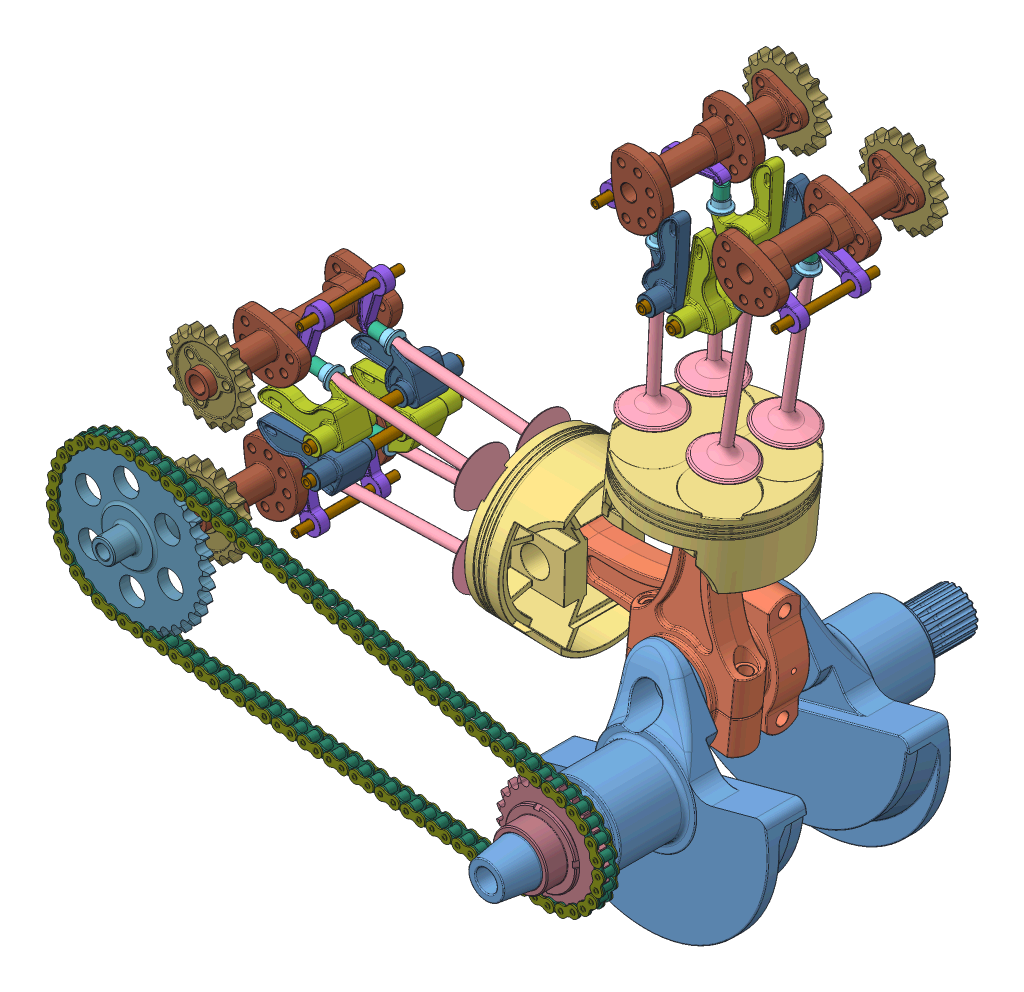
SolidWorks assembly Top Level Assembly, configuration Default. Lengths in mm.
Overall size (642.54 685.71 462).
171 component instances, 16 part files, 41 mates.
Components (placement in the parent):
- Flywheel Final-1: Flywheel Final [Taper Shaft] x (0.965926 0.258819 0) z (0 0 1) size (239.43 220 247)
- Conrod Final-1: Conrod Final [ConRod Cup] at (-15.5291 57.9555 -64) x (0.994894 -0.100925 0) z (0 0 1) size (117 45 42.18)
- Conrod Final-2: Conrod Final [ConRod] at (-15.5291 57.9555 -64) x (0.994894 -0.100925 0) z (0 0 1) size (117.32 192.67 42.18)
- Flywheel Final-2: Flywheel Final [Spline Shaft] at (0 0 -180) x (-0.965926 -0.258819 0) z (0 0 -1) size (239.43 220 215)
- Conrod Final-5: Conrod Final [ConRod Cup] at (-15.5291 57.9555 -116) x (-0.024908 -0.99969 0) z (0 0 -1) size (117 45 42.18)
- Conrod Final-6: Conrod Final [ConRod] at (-15.5291 57.9555 -116) x (-0.024908 -0.99969 0) z (0 0 -1) size (117.32 192.67 42.18)
- Piston and Cam Shaft Assembly-1: Piston and Cam Shaft Assembly [Default] at (5.0495 260.8144 -64) x (0 0 1) z (-0.994894 0.100925 0) size (194 330.08 197.81)
  - Piston Final-1: Piston Final [Default] at origin size (150 71.75 150)
  - Cam Assembly-1: Cam Assembly [Default] at (-257.3157 -28.0716 56.7677) size (194 233.48 197.81) (flexible)
    - Single Valves and Rockers-1: Single Valves and Rockers [Default] at (257.3157 26.5178 -56.6862) size (150 200.16 97.47)
      - Valve Final-5: Valve Final [Default] at (30 29.9426 -35.6104) x (-0.948904 -0.016515 -0.315132) z (0.315564 -0.049662 -0.947604) size (54 165 54)
      - Valve Final-6: Valve Final [Default] at (-30 29.9426 -35.6104) x (0.997243 -0.003884 -0.07411) z (0.074211 0.052192 0.995876) size (54 165 54)
      - Closing Shim-6: Closing Shim [Default] at (-30 174.7439 -43.1991) x (0.92869 -0.019409 -0.370348) z (0.370856 0.048604 0.927418) size (20 10 20)
      - Closing Shim-7: Closing Shim [Default] at (30 174.7439 -43.1991) x (0.998232 -0.003111 -0.059362) z (0.059443 0.052243 0.996864) size (20 10 20)
      - Opening Shim-5: Opening Shim [Default] at (-30 184.7302 -43.7225) x (1 0 0) z (0 0.052336 0.99863) size (12 13 12)
      - Opening Shim-6: Opening Shim [Default] at (30 184.7302 -43.7225) x (1 0 0) z (0 0.052336 0.99863) size (12 13 12)
      - Closing Rocker Arm_A-3: Closing Rocker Arm_A [Default] at (45 156.8153 -14.6663) x (0 -0.052336 -0.99863) z (1 0 0) size (41.82 83.99 55)
      - Opening Rocker Arm-3: Opening Rocker Arm [Default] at (-30 191.0023 -88.9874) x (0 0 1) z (-1 0 0) size (59.04 26.83 10.34)
      - Rocker Shafts-3: Rocker Shafts [Closing Rocker Shaft] at (0 156.8153 -14.6663) x (0 0 -1) z (1 0 0) size (10 10 150)
      - Closing Rocker Arm_B-4: Closing Rocker Arm_B [Default] at (-45 152.4639 -2.1604) x (0 -0.052336 -0.99863) z (1 0 0) size (41.82 83.99 55)
      - Opening Rocker Arm-4: Opening Rocker Arm [Default] at (30 191.0023 -88.9874) x (0 0 1) z (-1 0 0) size (59.04 26.83 10.34)
      - Rocker Shafts-4: Rocker Shafts [Opening Rocker Shaft] at (0 191.0023 -88.9874) x (0 -0.694346 -0.719642) z (1 0 0) size (8 8 100)
    - Single Valves and Rockers-2: Single Valves and Rockers [Default] at (257.3157 26.5178 -56.8491) x (-1 0 0) z (0 0 -1) size (150 200.16 97.47)
      - Valve Final-5: Valve Final [Default] at (30 29.9426 -35.6104) x (-0.948904 -0.016515 -0.315132) z (0.315564 -0.049662 -0.947604) size (54 165 54)
      - Valve Final-6: Valve Final [Default] at (-30 29.9426 -35.6104) x (0.997243 -0.003884 -0.07411) z (0.074211 0.052192 0.995876) size (54 165 54)
      - Closing Shim-6: Closing Shim [Default] at (-30 174.7439 -43.1991) x (0.92869 -0.019409 -0.370348) z (0.370856 0.048604 0.927418) size (20 10 20)
      - Closing Shim-7: Closing Shim [Default] at (30 174.7439 -43.1991) x (0.998232 -0.003111 -0.059362) z (0.059443 0.052243 0.996864) size (20 10 20)
      - Opening Shim-5: Opening Shim [Default] at (-30 184.7302 -43.7225) x (1 0 0) z (0 0.052336 0.99863) size (12 13 12)
      - Opening Shim-6: Opening Shim [Default] at (30 184.7302 -43.7225) x (1 0 0) z (0 0.052336 0.99863) size (12 13 12)
      - Closing Rocker Arm_A-3: Closing Rocker Arm_A [Default] at (45 156.8153 -14.6663) x (0 -0.052336 -0.99863) z (1 0 0) size (41.82 83.99 55)
      - Opening Rocker Arm-3: Opening Rocker Arm [Default] at (-30 191.0023 -88.9874) x (0 0 1) z (-1 0 0) size (59.04 26.83 10.34)
      - Rocker Shafts-3: Rocker Shafts [Closing Rocker Shaft] at (0 156.8153 -14.6663) x (0 0 -1) z (1 0 0) size (10 10 150)
      - Closing Rocker Arm_B-4: Closing Rocker Arm_B [Default] at (-45 152.4639 -2.1604) x (0 -0.052336 -0.99863) z (1 0 0) size (41.82 83.99 55)
      - Opening Rocker Arm-4: Opening Rocker Arm [Default] at (30 191.0023 -88.9874) x (0 0 1) z (-1 0 0) size (59.04 26.83 10.34)
      - Rocker Shafts-4: Rocker Shafts [Opening Rocker Shaft] at (0 191.0023 -88.9874) x (0 -0.694346 -0.719642) z (1 0 0) size (8 8 100)
    - Camshaft Final-2: Camshaft Final [Default] at (296.3157 248.3099 -114.2566) x (0 -0.958311 0.285728) z (1 0 0) size (53.08 66.16 170)
    - Camshaft Final-3: Camshaft Final [Default] at (296.3157 248.3099 0.7213) x (0 0.231707 -0.972786) z (1 0 0) size (53.08 66.16 170)
- Piston and Cam Shaft Assembly-2: Piston and Cam Shaft Assembly [Default] at (-219.3659 63.0343 -116) x (0 0 -1) z (0.024908 0.99969 0) size (194 330.08 197.81)
  - Piston Final-1: Piston Final [Default] at origin size (150 71.75 150)
  - Cam Assembly-1: Cam Assembly [Default] at (-257.3157 -28.0716 56.7677) size (194 233.48 197.81) (flexible)
    - Single Valves and Rockers-1: Single Valves and Rockers [Default] at (257.3157 26.5178 -56.6862) size (150 200.16 97.47)
      - Valve Final-5: Valve Final [Default] at (30 29.9426 -35.6104) x (-0.948904 -0.016515 -0.315132) z (0.315564 -0.049662 -0.947604) size (54 165 54)
      - Valve Final-6: Valve Final [Default] at (-30 29.9426 -35.6104) x (0.997243 -0.003884 -0.07411) z (0.074211 0.052192 0.995876) size (54 165 54)
      - Closing Shim-6: Closing Shim [Default] at (-30 174.7439 -43.1991) x (0.92869 -0.019409 -0.370348) z (0.370856 0.048604 0.927418) size (20 10 20)
      - Closing Shim-7: Closing Shim [Default] at (30 174.7439 -43.1991) x (0.998232 -0.003111 -0.059362) z (0.059443 0.052243 0.996864) size (20 10 20)
      - Opening Shim-5: Opening Shim [Default] at (-30 184.7302 -43.7225) x (1 0 0) z (0 0.052336 0.99863) size (12 13 12)
      - Opening Shim-6: Opening Shim [Default] at (30 184.7302 -43.7225) x (1 0 0) z (0 0.052336 0.99863) size (12 13 12)
      - Closing Rocker Arm_A-3: Closing Rocker Arm_A [Default] at (45 156.8153 -14.6663) x (0 -0.052336 -0.99863) z (1 0 0) size (41.82 83.99 55)
      - Opening Rocker Arm-3: Opening Rocker Arm [Default] at (-30 191.0023 -88.9874) x (0 0 1) z (-1 0 0) size (59.04 26.83 10.34)
      - Rocker Shafts-3: Rocker Shafts [Closing Rocker Shaft] at (0 156.8153 -14.6663) x (0 0 -1) z (1 0 0) size (10 10 150)
      - Closing Rocker Arm_B-4: Closing Rocker Arm_B [Default] at (-45 152.4639 -2.1604) x (0 -0.052336 -0.99863) z (1 0 0) size (41.82 83.99 55)
      - Opening Rocker Arm-4: Opening Rocker Arm [Default] at (30 191.0023 -88.9874) x (0 0 1) z (-1 0 0) size (59.04 26.83 10.34)
      - Rocker Shafts-4: Rocker Shafts [Opening Rocker Shaft] at (0 191.0023 -88.9874) x (0 -0.694346 -0.719642) z (1 0 0) size (8 8 100)
    - Single Valves and Rockers-2: Single Valves and Rockers [Default] at (257.3157 26.5178 -56.8491) x (-1 0 0) z (0 0 -1) size (150 200.16 97.47)
      - Valve Final-5: Valve Final [Default] at (30 29.9426 -35.6104) x (-0.948904 -0.016515 -0.315132) z (0.315564 -0.049662 -0.947604) size (54 165 54)
      - Valve Final-6: Valve Final [Default] at (-30 29.9426 -35.6104) x (0.997243 -0.003884 -0.07411) z (0.074211 0.052192 0.995876) size (54 165 54)
      - Closing Shim-6: Closing Shim [Default] at (-30 174.7439 -43.1991) x (0.92869 -0.019409 -0.370348) z (0.370856 0.048604 0.927418) size (20 10 20)
      - Closing Shim-7: Closing Shim [Default] at (30 174.7439 -43.1991) x (0.998232 -0.003111 -0.059362) z (0.059443 0.052243 0.996864) size (20 10 20)
      - Opening Shim-5: Opening Shim [Default] at (-30 184.7302 -43.7225) x (1 0 0) z (0 0.052336 0.99863) size (12 13 12)
      - Opening Shim-6: Opening Shim [Default] at (30 184.7302 -43.7225) x (1 0 0) z (0 0.052336 0.99863) size (12 13 12)
      - Closing Rocker Arm_A-3: Closing Rocker Arm_A [Default] at (45 156.8153 -14.6663) x (0 -0.052336 -0.99863) z (1 0 0) size (41.82 83.99 55)
      - Opening Rocker Arm-3: Opening Rocker Arm [Default] at (-30 191.0023 -88.9874) x (0 0 1) z (-1 0 0) size (59.04 26.83 10.34)
      - Rocker Shafts-3: Rocker Shafts [Closing Rocker Shaft] at (0 156.8153 -14.6663) x (0 0 -1) z (1 0 0) size (10 10 150)
      - Closing Rocker Arm_B-4: Closing Rocker Arm_B [Default] at (-45 152.4639 -2.1604) x (0 -0.052336 -0.99863) z (1 0 0) size (41.82 83.99 55)
      - Opening Rocker Arm-4: Opening Rocker Arm [Default] at (30 191.0023 -88.9874) x (0 0 1) z (-1 0 0) size (59.04 26.83 10.34)
      - Rocker Shafts-4: Rocker Shafts [Opening Rocker Shaft] at (0 191.0023 -88.9874) x (0 -0.694346 -0.719642) z (1 0 0) size (8 8 100)
    - Camshaft Final-2: Camshaft Final [Default] at (296.3157 248.3099 -114.2566) x (0 -0.958311 0.285728) z (1 0 0) size (53.08 66.16 170)
    - Camshaft Final-3: Camshaft Final [Default] at (296.3157 248.3099 0.7213) x (0 0.231707 -0.972786) z (1 0 0) size (53.08 66.16 170)
- Cam Gear Outer-1: Cam Gear Outer [Default] at (84.4724 474.1261 -169) x (-0.92458 0.380987 0) z (0 0 -1) size (80.56 81.63 12)
- Cam Gear Outer-2: Cam Gear Outer [Default] at (-29.9184 485.7303 -169) x (-0.92458 0.380987 0) z (0 0 -1) size (80.56 81.63 12)
- Cam Gear Outer-4: Cam Gear Outer [Default] at (-438.1039 125.991 -11) x (0.966712 -0.255865 0) z (0 0 1) size (80.56 81.63 12)
- Cam Gear Outer-5: Cam Gear Outer [Default] at (-440.9678 11.0488 -11) x (0.966712 -0.255865 0) z (0 0 1) size (80.56 81.63 12)
- Chain Assembly-1: Chain Assembly [Default] at (0 0 91) x (0.998355 0.057327 0) z (0 0 1) size (545.6 215.15 53)
  - Sprocket Small-2: Sprocket Small [Default] x (0.998956 0.045675 0) z (0 0 1) size (105.84 105.84 53)
  - Sprocket Large-2: Sprocket Large [Default] at (-407.7257 80 0) x (0.99997 0.007723 0) z (0 0 1) size (154.33 154.33 51)
  - Chain Link Inner-1: Chain Link Inner [Default] at (-296.9967 126.72 0) x (0.968404 -0.249386 0) z (0 0 1) size (24.21 11.51 13)
  - Chain Link Outer-1: Chain Link Outer [Default] at (-284.698 123.5528 0) x (0.968404 -0.249386 0) z (0 0 1) size (24.2 11.5 17)
  - Chain Link Inner-28: Chain Link Inner [Default] at (-321.5943 133.0544 0) x (0.968404 -0.249386 0) z (0 0 1) size (24.21 11.51 13)
  - Chain Link Inner-29: Chain Link Inner [Default] at (-346.1903 139.3884 0) x (0.968404 -0.249386 0) z (0 0 1) size (24.21 11.51 13)
  - Chain Link Inner-30: Chain Link Inner [Default] at (-370.7884 145.723 0) x (0.968404 -0.249386 0) z (0 0 1) size (24.21 11.51 13)
  - Chain Link Inner-31: Chain Link Inner [Default] at (-395.4395 151.8244 0) x (0.9851 -0.17198 0) z (0 0 1) size (24.21 11.51 13)
  - Chain Link Inner-32: Chain Link Inner [Default] at (-420.7229 152.0238 0) x (0.987542 0.157357 0) z (0 0 1) size (24.21 11.51 13)
  - Chain Link Inner-33: Chain Link Inner [Default] at (-444.6188 143.8052 0) x (0.872827 0.48803 0) z (0 0 1) size (24.21 11.51 13)
  - Chain Link Inner-34: Chain Link Inner [Default] at (-463.9737 127.5904 0) x (0.632224 0.774786 0) z (0 0 1) size (24.21 11.51 13)
  - Chain Link Inner-35: Chain Link Inner [Default] at (-476.1633 105.4564 0) x (0.326144 0.94532 0) z (0 0 1) size (24.21 11.51 13)
  - Chain Link Inner-36: Chain Link Inner [Default] at (-480.7851 80.5739 0) x (0.033588 0.999436 0) z (0 0 1) size (24.21 11.51 13)
  - Chain Link Inner-37: Chain Link Inner [Default] at (-477.2647 55.5543 0) x (-0.316746 0.94851 0) z (0 0 1) size (24.21 11.51 13)
  - Chain Link Inner-38: Chain Link Inner [Default] at (-464.9092 33.5332 0) x (-0.642872 0.765974 0) z (0 0 1) size (24.21 11.51 13)
  - Chain Link Inner-39: Chain Link Inner [Default] at (-445.501 17.351 0) x (-0.866485 0.499204 0) z (0 0 1) size (24.21 11.51 13)
  - Chain Link Inner-40: Chain Link Inner [Default] at (-421.8104 8.5113 0) x (-0.981598 0.19096 0) z (0 0 1) size (24.21 11.51 13)
  - Chain Link Inner-41: Chain Link Inner [Default] at (-396.6619 4.9605 0) x (-0.99084 0.135038 0) z (0 0 1) size (24.21 11.51 13)
  - Chain Link Inner-42: Chain Link Inner [Default] at (-371.4939 1.5304 0) x (-0.99084 0.135038 0) z (0 0 1) size (24.21 11.51 13)
  - Chain Link Inner-43: Chain Link Inner [Default] at (-346.328 -1.8993 0) x (-0.99084 0.135038 0) z (0 0 1) size (24.21 11.51 13)
  - Chain Link Inner-44: Chain Link Inner [Default] at (-321.16 -5.3294 0) x (-0.99084 0.135038 0) z (0 0 1) size (24.21 11.51 13)
  - Chain Link Inner-45: Chain Link Inner [Default] at (-295.992 -8.7594 0) x (-0.99084 0.135038 0) z (0 0 1) size (24.21 11.51 13)
  - Chain Link Inner-46: Chain Link Inner [Default] at (-270.8262 -12.1892 0) x (-0.99084 0.135038 0) z (0 0 1) size (24.21 11.51 13)
  - Chain Link Inner-47: Chain Link Inner [Default] at (-245.6582 -15.6192 0) x (-0.99084 0.135038 0) z (0 0 1) size (24.21 11.51 13)
  - Chain Link Inner-48: Chain Link Inner [Default] at (-220.4902 -19.0493 0) x (-0.99084 0.135038 0) z (0 0 1) size (24.21 11.51 13)
  - Chain Link Inner-49: Chain Link Inner [Default] at (-195.3222 -22.4793 0) x (-0.99084 0.135038 0) z (0 0 1) size (24.21 11.51 13)
  - Chain Link Inner-50: Chain Link Inner [Default] at (-170.1564 -25.9091 0) x (-0.99084 0.135038 0) z (0 0 1) size (24.21 11.51 13)
  - Chain Link Inner-51: Chain Link Inner [Default] at (-144.9884 -29.3391 0) x (-0.99084 0.135038 0) z (0 0 1) size (24.21 11.51 13)
  - Chain Link Inner-52: Chain Link Inner [Default] at (-119.8204 -32.7692 0) x (-0.99084 0.135038 0) z (0 0 1) size (24.21 11.51 13)
  - Chain Link Inner-53: Chain Link Inner [Default] at (-94.6546 -36.1989 0) x (-0.99084 0.135038 0) z (0 0 1) size (24.21 11.51 13)
  - Chain Link Outer-81: Chain Link Outer [Default] at (-309.2956 129.8872 0) x (0.968404 -0.249386 0) z (0 0 1) size (24.2 11.5 17)
  - Chain Link Outer-82: Chain Link Outer [Default] at (-333.8915 136.2212 0) x (0.968404 -0.249386 0) z (0 0 1) size (24.2 11.5 17)
  - Chain Link Outer-83: Chain Link Outer [Default] at (-358.4896 142.5558 0) x (0.968404 -0.249386 0) z (0 0 1) size (24.2 11.5 17)
  - Chain Link Outer-84: Chain Link Outer [Default] at (-383.0866 148.8901 0) x (0.968404 -0.249386 0) z (0 0 1) size (24.2 11.5 17)
  - Chain Link Outer-85: Chain Link Outer [Default] at (-408.0734 152.9694 0) x (0.999967 -0.008128 0) z (0 0 1) size (24.2 11.5 17)
  - Chain Link Outer-86: Chain Link Outer [Default] at (-433.0341 148.9673 0) x (0.94607 0.323963 0) z (0 0 1) size (24.2 11.5 17)
  - Chain Link Outer-87: Chain Link Outer [Default] at (-455.0644 136.614 0) x (0.766808 0.641877 0) z (0 0 1) size (24.2 11.5 17)
  - Chain Link Outer-88: Chain Link Outer [Default] at (-471.0484 117.065 0) x (0.48024 0.877137 0) z (0 0 1) size (24.2 11.5 17)
  - Chain Link Outer-89: Chain Link Outer [Default] at (-479.3816 93.1835 0) x (0.183322 0.983053 0) z (0 0 1) size (24.2 11.5 17)
  - Chain Link Outer-90: Chain Link Outer [Default] at (-480.145 67.9046 0) x (-0.137073 0.990561 0) z (0 0 1) size (24.2 11.5 17)
  - Chain Link Outer-91: Chain Link Outer [Default] at (-472.1278 43.9598 0) x (-0.489797 0.871837 0) z (0 0 1) size (24.2 11.5 17)
  - Chain Link Outer-92: Chain Link Outer [Default] at (-455.9144 24.5919 0) x (-0.768903 0.639365 0) z (0 0 1) size (24.2 11.5 17)
  - Chain Link Outer-93: Chain Link Outer [Default] at (-434.0212 11.9528 0) x (-0.936954 0.349454 0) z (0 0 1) size (24.2 11.5 17)
  - Chain Link Outer-94: Chain Link Outer [Default] at (-409.2448 6.6754 0) x (-0.99084 0.135038 0) z (0 0 1) size (24.2 11.5 17)
  - Chain Link Outer-95: Chain Link Outer [Default] at (-384.0775 3.2454 0) x (-0.99084 0.135038 0) z (0 0 1) size (24.2 11.5 17)
  - Chain Link Outer-96: Chain Link Outer [Default] at (-358.9117 -0.1843 0) x (-0.99084 0.135038 0) z (0 0 1) size (24.2 11.5 17)
  - Chain Link Outer-97: Chain Link Outer [Default] at (-333.7437 -3.6144 0) x (-0.99084 0.135038 0) z (0 0 1) size (24.2 11.5 17)
  - Chain Link Outer-98: Chain Link Outer [Default] at (-308.5757 -7.0444 0) x (-0.99084 0.135038 0) z (0 0 1) size (24.2 11.5 17)
  - Chain Link Outer-99: Chain Link Outer [Default] at (-283.4099 -10.4742 0) x (-0.99084 0.135038 0) z (0 0 1) size (24.2 11.5 17)
  - Chain Link Outer-100: Chain Link Outer [Default] at (-258.2419 -13.9042 0) x (-0.99084 0.135038 0) z (0 0 1) size (24.2 11.5 17)
  - Chain Link Outer-101: Chain Link Outer [Default] at (-233.0739 -17.3343 0) x (-0.99084 0.135038 0) z (0 0 1) size (24.2 11.5 17)
  - Chain Link Outer-102: Chain Link Outer [Default] at (-207.9059 -20.7643 0) x (-0.99084 0.135038 0) z (0 0 1) size (24.2 11.5 17)
  - Chain Link Outer-103: Chain Link Outer [Default] at (-182.7401 -24.1941 0) x (-0.99084 0.135038 0) z (0 0 1) size (24.2 11.5 17)
  - Chain Link Outer-104: Chain Link Outer [Default] at (-157.5721 -27.6241 0) x (-0.99084 0.135038 0) z (0 0 1) size (24.2 11.5 17)
  - Chain Link Outer-105: Chain Link Outer [Default] at (-132.4041 -31.0542 0) x (-0.99084 0.135038 0) z (0 0 1) size (24.2 11.5 17)
  - Chain Link Outer-106: Chain Link Outer [Default] at (-107.2382 -34.4839 0) x (-0.99084 0.135038 0) z (0 0 1) size (24.2 11.5 17)
  - Chain Link Inner-54: Chain Link Inner [Default] at (-69.4866 -39.629 0) x (-0.99084 0.135038 0) z (0 0 1) size (24.21 11.51 13)
  - Chain Link Inner-55: Chain Link Inner [Default] at (-44.3186 -43.059 0) x (-0.99084 0.135038 0) z (0 0 1) size (24.21 11.51 13)
  - Chain Link Inner-56: Chain Link Inner [Default] at (-19.1518 -46.4889 0) x (-0.99084 0.135038 0) z (0 0 1) size (24.21 11.51 13)
  - Chain Link Inner-57: Chain Link Inner [Default] at (6.0997 -48.4355 0) x (-0.995056 -0.099318 0) z (0 0 1) size (24.21 11.51 13)
  - Chain Link Inner-58: Chain Link Inner [Default] at (29.7963 -40.0164 0) x (-0.831452 -0.555596 0) z (0 0 1) size (24.21 11.51 13)
  - Chain Link Inner-59: Chain Link Inner [Default] at (46.3626 -21.1515 0) x (-0.437817 -0.899064 0) z (0 0 1) size (24.21 11.51 13)
  - Chain Link Inner-60: Chain Link Inner [Default] at (50.8144 3.5299 0) x (0.096024 -0.995379 0) z (0 0 1) size (24.21 11.51 13)
  - Chain Link Inner-61: Chain Link Inner [Default] at (41.8953 26.9986 0) x (0.584054 -0.811715 0) z (0 0 1) size (24.21 11.51 13)
  - Chain Link Inner-62: Chain Link Inner [Default] at (22.6637 43.2037 0) x (0.896382 -0.443283 0) z (0 0 1) size (24.21 11.51 13)
  - Chain Link Inner-63: Chain Link Inner [Default] at (-1.568 50.6403 0) x (0.968404 -0.249386 0) z (0 0 1) size (24.21 11.51 13)
  - Chain Link Inner-64: Chain Link Inner [Default] at (-26.1648 56.9745 0) x (0.968404 -0.249386 0) z (0 0 1) size (24.21 11.51 13)
  - Chain Link Inner-65: Chain Link Inner [Default] at (-50.7629 63.3091 0) x (0.968404 -0.249386 0) z (0 0 1) size (24.21 11.51 13)
  - Chain Link Inner-66: Chain Link Inner [Default] at (-75.361 69.6437 0) x (0.968404 -0.249386 0) z (0 0 1) size (24.21 11.51 13)
  - Chain Link Inner-67: Chain Link Inner [Default] at (-99.9569 75.9777 0) x (0.968404 -0.249386 0) z (0 0 1) size (24.21 11.51 13)
  - Chain Link Inner-68: Chain Link Inner [Default] at (-124.555 82.3123 0) x (0.968404 -0.249386 0) z (0 0 1) size (24.21 11.51 13)
  - Chain Link Inner-69: Chain Link Inner [Default] at (-149.1531 88.6469 0) x (0.968404 -0.249386 0) z (0 0 1) size (24.21 11.51 13)
  - Chain Link Inner-70: Chain Link Inner [Default] at (-173.7502 94.9812 0) x (0.968404 -0.249386 0) z (0 0 1) size (24.21 11.51 13)
  - Chain Link Inner-71: Chain Link Inner [Default] at (-198.3472 101.3155 0) x (0.968404 -0.249386 0) z (0 0 1) size (24.21 11.51 13)
  - Chain Link Inner-72: Chain Link Inner [Default] at (-222.9453 107.65 0) x (0.968404 -0.249386 0) z (0 0 1) size (24.21 11.51 13)
  - Chain Link Inner-73: Chain Link Inner [Default] at (-247.5434 113.9846 0) x (0.968404 -0.249386 0) z (0 0 1) size (24.21 11.51 13)
  - Chain Link Inner-74: Chain Link Inner [Default] at (-272.1394 120.3186 0) x (0.968404 -0.249386 0) z (0 0 1) size (24.21 11.51 13)
  - Chain Link Outer-107: Chain Link Outer [Default] at (-82.0703 -37.914 0) x (-0.99084 0.135038 0) z (0 0 1) size (24.2 11.5 17)
  - Chain Link Outer-108: Chain Link Outer [Default] at (-56.9023 -41.344 0) x (-0.99084 0.135038 0) z (0 0 1) size (24.2 11.5 17)
  - Chain Link Outer-109: Chain Link Outer [Default] at (-31.7353 -44.7739 0) x (-0.99084 0.135038 0) z (0 0 1) size (24.2 11.5 17)
  - Chain Link Outer-110: Chain Link Outer [Default] at (-6.5684 -48.2039 0) x (-0.990842 0.135027 0) z (0 0 1) size (24.2 11.5 17)
  - Chain Link Outer-111: Chain Link Outer [Default] at (18.4675 -45.6814 0) x (-0.942769 -0.333445 0) z (0 0 1) size (24.2 11.5 17)
  - Chain Link Outer-112: Chain Link Outer [Default] at (39.3354 -31.6842 0) x (-0.661029 -0.75036 0) z (0 0 1) size (24.2 11.5 17)
  - Chain Link Outer-113: Chain Link Outer [Default] at (50.2974 -9.1188 0) x (-0.17748 -0.984124 0) z (0 0 1) size (24.2 11.5 17)
  - Chain Link Outer-114: Chain Link Outer [Default] at (47.9132 15.8548 0) x (0.356765 -0.934194 0) z (0 0 1) size (24.2 11.5 17)
  - Chain Link Outer-115: Chain Link Outer [Default] at (33.2717 36.2787 0) x (0.76568 -0.643222 0) z (0 0 1) size (24.2 11.5 17)
  - Chain Link Outer-116: Chain Link Outer [Default] at (10.731 47.473 0) x (0.968404 -0.249386 0) z (0 0 1) size (24.2 11.5 17)
  - Chain Link Outer-117: Chain Link Outer [Default] at (-13.866 53.8073 0) x (0.968404 -0.249386 0) z (0 0 1) size (24.2 11.5 17)
  - Chain Link Outer-118: Chain Link Outer [Default] at (-38.4641 60.1419 0) x (0.968404 -0.249386 0) z (0 0 1) size (24.2 11.5 17)
  - Chain Link Outer-119: Chain Link Outer [Default] at (-63.0622 66.4765 0) x (0.968404 -0.249386 0) z (0 0 1) size (24.2 11.5 17)
  - Chain Link Outer-120: Chain Link Outer [Default] at (-87.6582 72.8105 0) x (0.968404 -0.249386 0) z (0 0 1) size (24.2 11.5 17)
  - Chain Link Outer-121: Chain Link Outer [Default] at (-112.2563 79.1451 0) x (0.968404 -0.249386 0) z (0 0 1) size (24.2 11.5 17)
  - Chain Link Outer-122: Chain Link Outer [Default] at (-136.8544 85.4796 0) x (0.968404 -0.249386 0) z (0 0 1) size (24.2 11.5 17)
  - Chain Link Outer-123: Chain Link Outer [Default] at (-161.4514 91.8139 0) x (0.968404 -0.249386 0) z (0 0 1) size (24.2 11.5 17)
  - Chain Link Outer-124: Chain Link Outer [Default] at (-186.0485 98.1482 0) x (0.968404 -0.249386 0) z (0 0 1) size (24.2 11.5 17)
  - Chain Link Outer-125: Chain Link Outer [Default] at (-210.6466 104.4828 0) x (0.968404 -0.249386 0) z (0 0 1) size (24.2 11.5 17)
  - Chain Link Outer-126: Chain Link Outer [Default] at (-235.2447 110.8174 0) x (0.968404 -0.249386 0) z (0 0 1) size (24.2 11.5 17)
  - Chain Link Outer-127: Chain Link Outer [Default] at (-259.8407 117.1514 0) x (0.968404 -0.249386 0) z (0 0 1) size (24.2 11.5 17)
Mates (geometry in assembly coordinates):
- Coincident1: coincident aligned: plane of Flywheel Final-1 through (0 0 0) normal (0 0 1); plane of assembly through (0 0 0) normal (0 0 1)
- Angle1: planar angle = 0.261799 rad aligned: plane of Flywheel Final-1 through (0 0 -308.3282) normal (-0.258819 0.965926 0); plane of assembly through (0 0 0) normal (0 1 0)
- Coincident2: coincident: point of Flywheel Final-1
- Concentric1: concentric anti-aligned: cylinder of Flywheel Final-1 through (-15.5291 57.9555 -90) axis (0 0 1) radius 30; cylinder of Conrod Final-1 through (-15.5291 57.9555 -43) axis (0 0 -1) radius 32.5
- Distance1: distance = 3 mm anti-aligned: plane of Conrod Final-1 through (-15.5291 57.9555 -43) normal (0 0 1); plane of Flywheel Final-1 through (0 0 -40) normal (0 0 -1)
- Concentric2: concentric anti-aligned: cylinder of Flywheel Final-1 through (-15.5291 57.9555 -90) axis (0 0 1) radius 30; cylinder of Conrod Final-2 through (-15.5291 57.9555 -43) axis (0 0 -1) radius 32.5
- Distance2: distance = 3 mm anti-aligned: plane of Conrod Final-2 through (-15.5291 57.9555 -43) normal (0 0 1); plane of Flywheel Final-1 through (0 0 -40) normal (0 0 -1)
- Coincident4: coincident anti-aligned: plane of Conrod Final-1 through (-15.5291 57.9555 -64) normal (0.100925 0.994894 0); plane of Conrod Final-2 through (-15.5291 57.9555 -64) normal (-0.100925 -0.994894 0)
- Concentric3: concentric anti-aligned: cylinder of Flywheel Final-1 through (-15.5291 57.9555 -90) axis (0 0 1) radius 30; cylinder of Flywheel Final-2 through (-15.5291 57.9555 -90) axis (0 0 -1) radius 30
- Coincident5: coincident anti-aligned: plane of Flywheel Final-1 through (-15.5291 57.9555 -90) normal (0 0 -1); plane of Flywheel Final-2 through (-15.5291 57.9555 -90) normal (0 0 1)
- Parallel1: parallel aligned: plane of Flywheel Final-1 through (0 0 -308.3282) normal (-0.258819 0.965926 0); plane of Flywheel Final-2 through (0 0 128.3282) normal (-0.258819 0.965926 0)
- Concentric6: concentric anti-aligned: cylinder of Flywheel Final-2 through (-15.5291 57.9555 -90) axis (0 0 -1) radius 30; cylinder of Conrod Final-5 through (-15.5291 57.9555 -137) axis (0 0 1) radius 32.5
- Distance5: distance = 3 mm anti-aligned: plane of Conrod Final-5 through (-15.5291 57.9555 -137) normal (0 0 -1); plane of Flywheel Final-2 through (0 0 -140) normal (0 0 1)
- Concentric7: concentric anti-aligned: cylinder of Flywheel Final-2 through (-15.5291 57.9555 -90) axis (0 0 -1) radius 30; cylinder of Conrod Final-6 through (-15.5291 57.9555 -137) axis (0 0 1) radius 32.5
- Distance6: distance = 3 mm anti-aligned: plane of Conrod Final-6 through (-15.5291 57.9555 -137) normal (0 0 -1); plane of Flywheel Final-2 through (0 0 -140) normal (0 0 1)
- Coincident6: coincident anti-aligned: plane of Conrod Final-5 through (-15.5291 57.9555 -116) normal (-0.99969 0.024908 0); plane of Conrod Final-6 through (-15.5291 57.9555 -116) normal (0.99969 -0.024908 0)
- Concentric8: concentric anti-aligned: cylinder of Conrod Final-2 through (1.6281 227.0875 -43) axis (0 0 -1) radius 14.6716; cylinder of Piston and Cam Shaft Assembly-1/Piston Final-1 through (1.6281 227.0875 -142.8151) axis (0 0 1) radius 13.9
- Parallel2: parallel aligned: plane of Conrod Final-2 through (34.0135 85.5966 -64) normal (0.100925 0.994894 0); plane of Piston and Cam Shaft Assembly-1/Piston Final-1 through (5.0495 260.8144 -64) normal (0.100925 0.994894 0)
- Width1: width anti-aligned: plane of Conrod Final-2 through (18.8916 122.3102 -48) normal (0 0 1); plane of Conrod Final-2 through (18.8916 122.3102 -80) normal (0 0 -1); plane of Piston and Cam Shaft Assembly-1/Piston Final-1 through (-14.8929 306.9818 -103.5) normal (0 0 -1); plane of Piston and Cam Shaft Assembly-1/Piston Final-1 through (-14.8929 306.9818 -24.5) normal (0 0 1)
- Concentric9: concentric anti-aligned: cylinder of Conrod Final-6 through (-185.4764 62.1899 -137) axis (0 0 1) radius 14.6716; cylinder of Piston and Cam Shaft Assembly-2/Piston Final-1 through (-185.4764 62.1899 -37.1849) axis (0 0 -1) radius 13.9
- Parallel3: parallel aligned: plane of Conrod Final-6 through (-46.8608 105.2506 -116) normal (-0.99969 0.024908 0); plane of Piston and Cam Shaft Assembly-2/Piston Final-1 through (-219.3659 63.0343 -116) normal (-0.99969 0.024908 0)
- Width2: width anti-aligned: plane of Conrod Final-6 through (-83.6994 31.8954 -100) normal (0 0 1); plane of Conrod Final-6 through (-83.6994 31.8954 -132) normal (0 0 -1); plane of Piston and Cam Shaft Assembly-2/Piston Final-1 through (-262.6609 88.6206 -155.5) normal (0 0 -1); plane of Piston and Cam Shaft Assembly-2/Piston Final-1 through (-262.6609 88.6206 -76.5) normal (0 0 1)
- Concentric10: concentric anti-aligned: cylinder of Piston and Cam Shaft Assembly-1/Cam Assembly-1/Camshaft Final-2 through (84.4724 474.1261 -183) axis (0 0 1) radius 12; cylinder of Cam Gear Outer-1 through (84.4724 474.1261 -163) axis (0 0 -1) radius 12
- Coincident7: coincident anti-aligned: plane of Piston and Cam Shaft Assembly-1/Cam Assembly-1/Camshaft Final-2 through (74.709 486.8019 -163) normal (0 0 -1); plane of Cam Gear Outer-1 through (84.4724 474.1261 -163) normal (0 0 1)
- Concentric11: concentric aligned: cylinder of Piston and Cam Shaft Assembly-1/Cam Assembly-1/Camshaft Final-2 through (105.2877 476.9054 -163) axis (0 0 -1) radius 3.5; cylinder of Cam Gear Outer-1 through (105.2877 476.9054 -163) axis (0 0 -1) radius 3.5
- Concentric12: concentric aligned: cylinder of Piston and Cam Shaft Assembly-1/Cam Assembly-1/Camshaft Final-2 through (71.6579 490.7631 -163) axis (0 0 -1) radius 3.5; cylinder of Cam Gear Outer-1 through (71.6579 490.7631 -163) axis (0 0 -1) radius 3.5
- Concentric13: concentric anti-aligned: cylinder of Piston and Cam Shaft Assembly-1/Cam Assembly-1/Camshaft Final-3 through (-29.9184 485.7303 -183) axis (0 0 1) radius 12; cylinder of Cam Gear Outer-2 through (-29.9184 485.7303 -163) axis (0 0 -1) radius 12
- Coincident8: coincident anti-aligned: plane of Piston and Cam Shaft Assembly-1/Cam Assembly-1/Camshaft Final-3 through (-36.0142 470.937 -163) normal (0 0 -1); plane of Cam Gear Outer-2 through (-29.9184 485.7303 -163) normal (0 0 1)
- Concentric14: concentric aligned: cylinder of Piston and Cam Shaft Assembly-1/Cam Assembly-1/Camshaft Final-3 through (-9.1031 488.5095 -163) axis (0 0 -1) radius 3.5; cylinder of Cam Gear Outer-2 through (-9.1031 488.5095 -163) axis (0 0 -1) radius 3.5
- Concentric15: concentric aligned: cylinder of Piston and Cam Shaft Assembly-1/Cam Assembly-1/Camshaft Final-3 through (-42.7329 502.3672 -163) axis (0 0 -1) radius 3.5; cylinder of Cam Gear Outer-2 through (-42.7329 502.3672 -163) axis (0 0 -1) radius 3.5
- Concentric17: concentric anti-aligned: cylinder of Piston and Cam Shaft Assembly-2/Cam Assembly-1/Camshaft Final-3 through (-438.1039 125.991 3) axis (0 0 -1) radius 12; cylinder of Cam Gear Outer-4 through (-438.1039 125.991 -17) axis (0 0 1) radius 12
- Coincident10: coincident anti-aligned: plane of Piston and Cam Shaft Assembly-2/Cam Assembly-1/Camshaft Final-3 through (-422.6618 130.1794 -17) normal (0 0 1); plane of Cam Gear Outer-4 through (-438.1039 125.991 -17) normal (0 0 -1)
- Concentric18: concentric aligned: cylinder of Piston and Cam Shaft Assembly-2/Cam Assembly-1/Camshaft Final-3 through (-452.9985 140.7948 -17) axis (0 0 1) radius 3.5; cylinder of Cam Gear Outer-4 through (-452.9985 140.7948 -17) axis (0 0 1) radius 3.5
- Concentric19: concentric aligned: cylinder of Piston and Cam Shaft Assembly-2/Cam Assembly-1/Camshaft Final-3 through (-417.8362 131.4882 -17) axis (0 0 1) radius 3.5; cylinder of Cam Gear Outer-4 through (-417.8362 131.4882 -17) axis (0 0 1) radius 3.5
- Concentric20: concentric anti-aligned: cylinder of Piston and Cam Shaft Assembly-2/Cam Assembly-1/Camshaft Final-2 through (-440.9678 11.0488 3) axis (0 0 -1) radius 12; cylinder of Cam Gear Outer-5 through (-440.9678 11.0488 -17) axis (0 0 1) radius 12
- Coincident11: coincident anti-aligned: plane of Piston and Cam Shaft Assembly-2/Cam Assembly-1/Camshaft Final-2 through (-452.316 22.3279 -17) normal (0 0 1); plane of Cam Gear Outer-5 through (-440.9678 11.0488 -17) normal (0 0 -1)
- Concentric21: concentric aligned: cylinder of Piston and Cam Shaft Assembly-2/Cam Assembly-1/Camshaft Final-2 through (-455.8623 25.8526 -17) axis (0 0 1) radius 3.5; cylinder of Cam Gear Outer-5 through (-455.8623 25.8526 -17) axis (0 0 1) radius 3.5
- Concentric22: concentric aligned: cylinder of Piston and Cam Shaft Assembly-2/Cam Assembly-1/Camshaft Final-2 through (-420.7 16.546 -17) axis (0 0 1) radius 3.5; cylinder of Cam Gear Outer-5 through (-420.7 16.546 -17) axis (0 0 1) radius 3.5
- Concentric23: concentric aligned: cylinder of Flywheel Final-1 through (0 0 125) axis (0 0 1) radius 22; cylinder of Chain Assembly-1/Sprocket Small-2 through (0 0 71) axis (0 0 1) radius 22
- Coincident12: coincident anti-aligned: plane of Flywheel Final-1 through (-8.7998 32.8415 71) normal (0 0 1); plane of Chain Assembly-1/Sprocket Small-2 through (0 0 71) normal (0 0 -1)
- Concentric24: concentric aligned: cylinder of Piston and Cam Shaft Assembly-2/Cam Assembly-1/Single Valves and Rockers-2/Closing Rocker Arm_A-3 through (-374.216 81.4818 -101) axis (0 0 1) radius 9; cylinder of Chain Assembly-1/Sprocket Large-2 through (-374.216 81.4818 71) axis (0 0 1) radius 12.5
